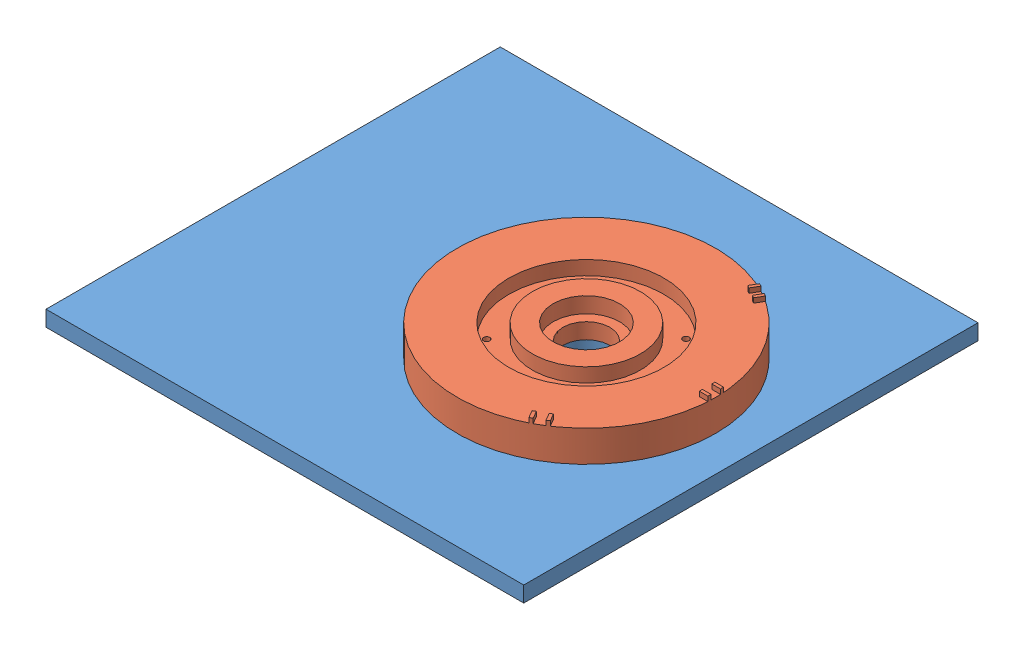
SolidWorks assembly Assem1, configuration Default. Lengths in mm.
Overall size (305 33 290).
2 component instances, 2 part files, 2 mates.
Components (placement in the parent):
- tren2-1: tren2 [Default] at origin size (305 10 290)
- dem tren-2: dem tren [Default] at (25 10 0) x (0.002526 0 0.999997) z (-0.999997 0 0.002526) size (165 23 165)
Mates (geometry in assembly coordinates):
- Coincident1: coincident: plane of assembly; plane of assembly; plane of tren2-1 through (0 10 0) normal (0 1 0); plane of dem tren-2 through (25 10 0) normal (0 -1 0)
- Concentric1: concentric: cylinder of assembly; cylinder of assembly; cylinder of tren2-1 through (25 10 0) axis (0 -1 0) radius 17.5; cylinder of dem tren-2 through (25 10 0) axis (0 1 0) radius 15
